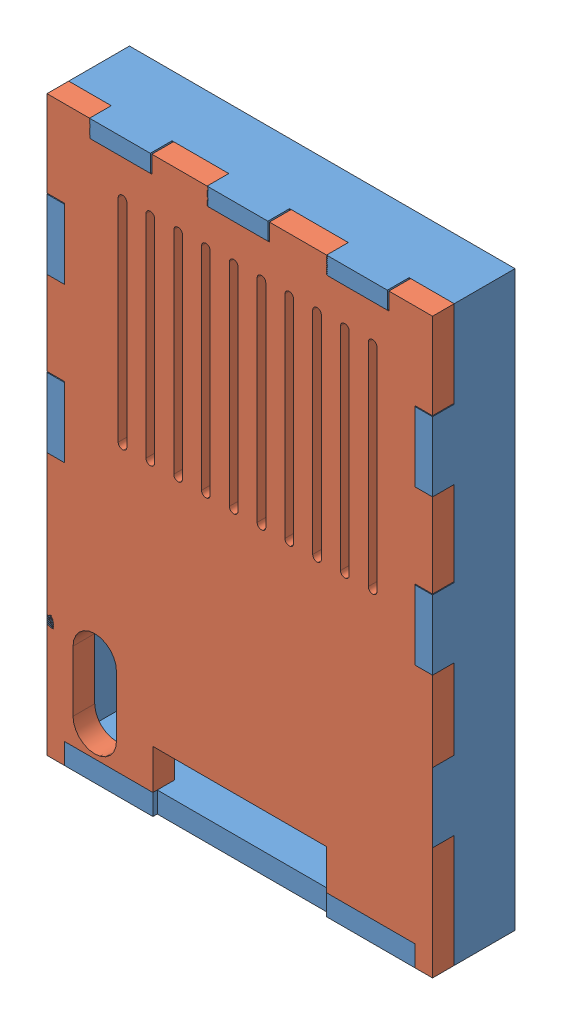
SolidWorks assembly Montagem1, configuration Valor predeterminado. Lengths in mm.
Overall size (44.4 66 9.5).
2 component instances, 2 part files, 1 mates.
Components (placement in the parent):
- base-1: base [Valor predeterminado] at (4.4919 16.2565 66) size (44.4 66 9.5)
- topo-2: topo [Valor predeterminado] at (4.8964 16.9798 73) size (44.4 66 2.5)
Mates (geometry in assembly coordinates):
- Coincidente1: coincident: point of base-1; point of topo-2
